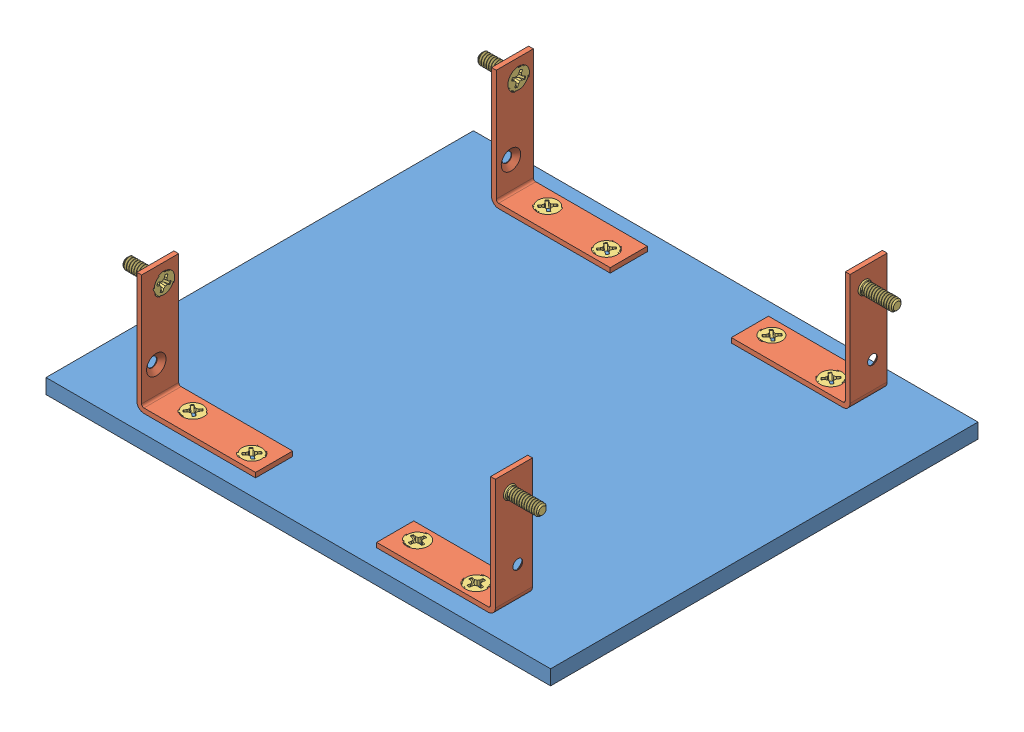
SolidWorks assembly middle shelf, configuration Default. Lengths in mm.
Overall size (215.9 65.04 182.88).
25 component instances, 4 part files, 43 mates.
Components (placement in the parent):
- shelf-1: shelf [Default] at (81.5847 84.2662 165.5831) size (215.9 6.35 182.88)
- 1556A540_BRACKET-1: 1556A540_BRACKET [1556A54] at (4.8767 90.6162 241.4656) x (1 0 0) z (0 1 0) size (50.8 15.88 50.8)
- 1556A540_BRACKET-2: 1556A540_BRACKET [1556A54] at (158.2927 90.6162 241.4656) x (-1 0 0) z (0 1 0) size (50.8 15.88 50.8)
- 1556A540_BRACKET-3: 1556A540_BRACKET [1556A54] at (4.8767 90.6162 89.7006) x (1 0 0) z (0 1 0) size (50.8 15.88 50.8)
- 1556A540_BRACKET-4: 1556A540_BRACKET [1556A54] at (158.2927 90.6162 89.7006) x (-1 0 0) z (0 1 0) size (50.8 15.88 50.8)
- 91771A244_18-8 SS FLAT HEAD PHILLIPS MACHINE SCREW-1: 91771A244_18-8 SS FLAT HEAD PHILLIPS MACHINE SCREW [91771A244] at (19.3547 89.7018 239.8146) x (0.631419 0 -0.775441) z (0 1 0) size (9.19 9.19 16.27)
- 91771A244_18-8 SS FLAT HEAD PHILLIPS MACHINE SCREW-2: 91771A244_18-8 SS FLAT HEAD PHILLIPS MACHINE SCREW [91771A244] at (47.8027 89.7018 243.1166) x (0.630362 0 -0.776302) z (0 1 0) size (9.19 9.19 16.27)
- 91771A244_18-8 SS FLAT HEAD PHILLIPS MACHINE SCREW-3: 91771A244_18-8 SS FLAT HEAD PHILLIPS MACHINE SCREW [91771A244] at (115.3667 89.7018 239.8146) x (0.160382 0 -0.987055) z (0 1 0) size (9.19 9.19 16.27)
- 91771A244_18-8 SS FLAT HEAD PHILLIPS MACHINE SCREW-4: 91771A244_18-8 SS FLAT HEAD PHILLIPS MACHINE SCREW [91771A244] at (143.8147 89.7018 243.1166) x (0.160382 0 -0.987055) z (0 1 0) size (9.19 9.19 16.27)
- 91771A244_18-8 SS FLAT HEAD PHILLIPS MACHINE SCREW-5: 91771A244_18-8 SS FLAT HEAD PHILLIPS MACHINE SCREW [91771A244] at (19.3547 89.7018 88.0496) x (0.631419 0 -0.775441) z (0 1 0) size (9.19 9.19 16.27)
- 91771A244_18-8 SS FLAT HEAD PHILLIPS MACHINE SCREW-6: 91771A244_18-8 SS FLAT HEAD PHILLIPS MACHINE SCREW [91771A244] at (47.8027 89.7018 91.3516) x (0.631419 0 -0.775441) z (0 1 0) size (9.19 9.19 16.27)
- 91771A244_18-8 SS FLAT HEAD PHILLIPS MACHINE SCREW-7: 91771A244_18-8 SS FLAT HEAD PHILLIPS MACHINE SCREW [91771A244] at (115.3667 89.7018 88.0496) x (0.631419 0 -0.775441) z (0 1 0) size (9.19 9.19 16.27)
- 91771A244_18-8 SS FLAT HEAD PHILLIPS MACHINE SCREW-8: 91771A244_18-8 SS FLAT HEAD PHILLIPS MACHINE SCREW [91771A244] at (143.8147 89.7018 91.3516) x (0.631419 0 -0.775441) z (0 1 0) size (9.19 9.19 16.27)
- 91771A244_18-8 SS FLAT HEAD PHILLIPS MACHINE SCREW-9: 91771A244_18-8 SS FLAT HEAD PHILLIPS MACHINE SCREW [91771A244] at (3.9623 133.5422 239.8146) x (0 0.931939 -0.362615) z (1 0 0) size (9.19 9.19 16.27)
- 91771A244_18-8 SS FLAT HEAD PHILLIPS MACHINE SCREW-11: 91771A244_18-8 SS FLAT HEAD PHILLIPS MACHINE SCREW [91771A244] at (3.9623 133.5422 88.0496) x (0 0.931939 -0.362615) z (1 0 0) size (9.19 9.19 16.27)
- 91771A244_18-8 SS FLAT HEAD PHILLIPS MACHINE SCREW-12: 91771A244_18-8 SS FLAT HEAD PHILLIPS MACHINE SCREW [91771A244] at (159.2071 133.5422 91.3516) x (0 -0.881722 -0.471769) z (-1 0 0) size (9.19 9.19 16.27)
- 91771A244_18-8 SS FLAT HEAD PHILLIPS MACHINE SCREW-13: 91771A244_18-8 SS FLAT HEAD PHILLIPS MACHINE SCREW [91771A244] at (159.2071 133.5422 243.1166) x (0 -0.832179 -0.554507) z (-1 0 0) size (9.19 9.19 16.27)
- 90480A011_LOW-STRENGTH STEEL HEX NUT-1: 90480A011_LOW-STRENGTH STEEL HEX NUT [90480A011] at (19.3547 82.6787 239.8146) x (0.837169 0 0.546944) z (-0.546944 0 0.837169) size (9.53 3.99 11)
- 90480A011_LOW-STRENGTH STEEL HEX NUT-2: 90480A011_LOW-STRENGTH STEEL HEX NUT [90480A011] at (47.8027 82.6787 243.1166) x (-0.837169 0 0.546944) z (0.546944 0 0.837169) size (9.53 3.99 11)
- 90480A011_LOW-STRENGTH STEEL HEX NUT-3: 90480A011_LOW-STRENGTH STEEL HEX NUT [90480A011] at (115.3667 82.6787 239.8146) x (-0.837169 0 0.546944) z (0.546944 0 0.837169) size (9.53 3.99 11)
- 90480A011_LOW-STRENGTH STEEL HEX NUT-4: 90480A011_LOW-STRENGTH STEEL HEX NUT [90480A011] at (143.8147 82.6787 243.1166) x (-0.837169 0 0.546944) z (0.546944 0 0.837169) size (9.53 3.99 11)
- 90480A011_LOW-STRENGTH STEEL HEX NUT-5: 90480A011_LOW-STRENGTH STEEL HEX NUT [90480A011] at (19.3547 82.6787 88.0496) x (0.837169 0 0.546944) z (0.546944 0 -0.837169) size (9.53 3.99 11)
- 90480A011_LOW-STRENGTH STEEL HEX NUT-6: 90480A011_LOW-STRENGTH STEEL HEX NUT [90480A011] at (47.8027 82.6787 91.3516) x (-0.401704 0 -0.915769) z (0.915769 0 -0.401704) size (9.53 3.99 11)
- 90480A011_LOW-STRENGTH STEEL HEX NUT-7: 90480A011_LOW-STRENGTH STEEL HEX NUT [90480A011] at (115.3667 82.6787 88.0496) x (0.837169 0 0.546944) z (0.546944 0 -0.837169) size (9.53 3.99 11)
- 90480A011_LOW-STRENGTH STEEL HEX NUT-8: 90480A011_LOW-STRENGTH STEEL HEX NUT [90480A011] at (143.8147 82.6787 91.3516) x (-0.401704 0 -0.915769) z (0.915769 0 -0.401704) size (9.53 3.99 11)
Mates (geometry in assembly coordinates):
- Coincident1: coincident anti-aligned: plane of shelf-1 through (81.5847 90.6162 165.5831) normal (0 1 0); plane of 1556A540_BRACKET-1 through (7.9247 90.6162 233.5281) normal (0 -1 0)
- Distance1: distance = 34.29 mm: line of 1556A540_BRACKET-1 through (7.9247 90.6162 233.5281) axis (0 0 1); line of shelf-1 through (-26.3653 90.6162 74.1431) axis (0 0 1)
- Distance2: distance = 7.62 mm: line of 1556A540_BRACKET-1 through (7.9247 90.6162 249.4031) axis (1 0 0); line of shelf-1 through (-26.3653 90.6162 257.0231) axis (1 0 0)
- Concentric1: concentric aligned: circle of 1556A540_BRACKET-1; circle of 91771A244_18-8 SS FLAT HEAD PHILLIPS MACHINE SCREW-1
- Coincident2: coincident aligned: plane of 1556A540_BRACKET-1 through (7.9247 92.6482 233.5281) normal (0 1 0); plane of 91771A244_18-8 SS FLAT HEAD PHILLIPS MACHINE SCREW-1 through (17.4836 92.6482 238.291) normal (0 1 0)
- Concentric2: concentric aligned: circle of 1556A540_BRACKET-2; circle of 91771A244_18-8 SS FLAT HEAD PHILLIPS MACHINE SCREW-4
- Coincident3: coincident aligned: plane of 1556A540_BRACKET-2 through (155.2447 92.6482 249.4031) normal (0 1 0); plane of 91771A244_18-8 SS FLAT HEAD PHILLIPS MACHINE SCREW-4 through (141.433 92.6482 242.7296) normal (0 1 0)
- Concentric3: concentric aligned: circle of 1556A540_BRACKET-2; circle of 91771A244_18-8 SS FLAT HEAD PHILLIPS MACHINE SCREW-3
- Coincident4: coincident aligned: plane of 1556A540_BRACKET-2 through (155.2447 92.6482 249.4031) normal (0 1 0); plane of 91771A244_18-8 SS FLAT HEAD PHILLIPS MACHINE SCREW-3 through (112.985 92.6482 239.4276) normal (0 1 0)
- Coincident5: coincident aligned: plane of 1556A540_BRACKET-1 through (7.9247 92.6482 233.5281) normal (0 1 0); plane of 91771A244_18-8 SS FLAT HEAD PHILLIPS MACHINE SCREW-2 through (45.9295 92.6482 241.5955) normal (0 1 0)
- Concentric4: concentric aligned: circle of 1556A540_BRACKET-1; circle of 91771A244_18-8 SS FLAT HEAD PHILLIPS MACHINE SCREW-2
- Coincident6: coincident aligned: plane of 1556A540_BRACKET-3 through (7.9247 92.6482 81.7631) normal (0 1 0); plane of 91771A244_18-8 SS FLAT HEAD PHILLIPS MACHINE SCREW-5 through (17.4836 92.6482 86.526) normal (0 1 0)
- Coincident7: coincident aligned: plane of 1556A540_BRACKET-3 through (7.9247 92.6482 81.7631) normal (0 1 0); plane of 91771A244_18-8 SS FLAT HEAD PHILLIPS MACHINE SCREW-6 through (45.9316 92.6482 89.828) normal (0 1 0)
- Concentric5: concentric aligned: cone of 1556A540_BRACKET-3 through (47.8027 90.9006 91.3516) axis (0 -1 0); circle of 91771A244_18-8 SS FLAT HEAD PHILLIPS MACHINE SCREW-6
- Concentric6: concentric aligned: circle of 1556A540_BRACKET-3; circle of 91771A244_18-8 SS FLAT HEAD PHILLIPS MACHINE SCREW-5
- Coincident8: coincident aligned: plane of 1556A540_BRACKET-4 through (155.2447 92.6482 97.6381) normal (0 1 0); plane of 91771A244_18-8 SS FLAT HEAD PHILLIPS MACHINE SCREW-7 through (113.4956 92.6482 86.526) normal (0 1 0)
- Concentric7: concentric aligned: circle of 1556A540_BRACKET-4; circle of 91771A244_18-8 SS FLAT HEAD PHILLIPS MACHINE SCREW-7
- Coincident9: coincident aligned: plane of 1556A540_BRACKET-4 through (155.2447 92.6482 97.6381) normal (0 1 0); plane of 91771A244_18-8 SS FLAT HEAD PHILLIPS MACHINE SCREW-8 through (141.9436 92.6482 89.828) normal (0 1 0)
- Concentric8: concentric aligned: circle of 1556A540_BRACKET-4; circle of 91771A244_18-8 SS FLAT HEAD PHILLIPS MACHINE SCREW-8
- Coincident12: coincident aligned: plane of 1556A540_BRACKET-1 through (6.9087 141.4162 233.5281) normal (1 0 0); plane of 91771A244_18-8 SS FLAT HEAD PHILLIPS MACHINE SCREW-9 through (6.9087 134.4172 242.0634) normal (1 0 0)
- Concentric9: concentric aligned: circle of 1556A540_BRACKET-1; circle of 91771A244_18-8 SS FLAT HEAD PHILLIPS MACHINE SCREW-9
- Coincident13: coincident aligned: plane of 1556A540_BRACKET-3 through (6.9087 141.4162 81.7631) normal (1 0 0); plane of 91771A244_18-8 SS FLAT HEAD PHILLIPS MACHINE SCREW-11 through (6.9087 134.4172 90.2984) normal (1 0 0)
- Concentric10: concentric aligned: circle of 1556A540_BRACKET-3; circle of 91771A244_18-8 SS FLAT HEAD PHILLIPS MACHINE SCREW-11
- Coincident14: coincident aligned: plane of 1556A540_BRACKET-4 through (156.2607 141.4162 97.6381) normal (-1 0 0); plane of 91771A244_18-8 SS FLAT HEAD PHILLIPS MACHINE SCREW-12 through (156.2607 132.4039 93.4792) normal (-1 0 0)
- Concentric11: concentric aligned: circle of 1556A540_BRACKET-4; circle of 91771A244_18-8 SS FLAT HEAD PHILLIPS MACHINE SCREW-12
- Concentric12: concentric aligned: circle of 1556A540_BRACKET-2; circle of 91771A244_18-8 SS FLAT HEAD PHILLIPS MACHINE SCREW-13
- Coincident15: coincident aligned: plane of 1556A540_BRACKET-2 through (156.2607 141.4162 249.4031) normal (-1 0 0); plane of 91771A244_18-8 SS FLAT HEAD PHILLIPS MACHINE SCREW-13 through (156.2607 132.2042 245.1246) normal (-1 0 0)
- Coincident17: coincident anti-aligned: plane of shelf-1 through (81.5847 84.2662 165.5831) normal (0 -1 0); plane of 90480A011_LOW-STRENGTH STEEL HEX NUT-1 through (16.8716 84.2662 234.9079) normal (0 1 0)
- Concentric13: concentric anti-aligned: circle of 91771A244_18-8 SS FLAT HEAD PHILLIPS MACHINE SCREW-1; circle of 90480A011_LOW-STRENGTH STEEL HEX NUT-1
- Concentric14: concentric aligned: circle of 91771A244_18-8 SS FLAT HEAD PHILLIPS MACHINE SCREW-2; circle of 90480A011_LOW-STRENGTH STEEL HEX NUT-2
- Coincident18: coincident anti-aligned: plane of shelf-1 through (81.5847 84.2662 165.5831) normal (0 -1 0); plane of 90480A011_LOW-STRENGTH STEEL HEX NUT-2 through (50.2859 84.2662 238.2099) normal (0 1 0)
- Concentric15: concentric aligned: circle of 91771A244_18-8 SS FLAT HEAD PHILLIPS MACHINE SCREW-3; circle of 90480A011_LOW-STRENGTH STEEL HEX NUT-3
- Concentric16: concentric aligned: circle of 91771A244_18-8 SS FLAT HEAD PHILLIPS MACHINE SCREW-4; circle of 90480A011_LOW-STRENGTH STEEL HEX NUT-4
- Coincident19: coincident anti-aligned: plane of shelf-1 through (81.5847 84.2662 165.5831) normal (0 -1 0); plane of 90480A011_LOW-STRENGTH STEEL HEX NUT-3 through (117.8499 84.2662 234.9079) normal (0 1 0)
- Coincident20: coincident anti-aligned: plane of shelf-1 through (81.5847 84.2662 165.5831) normal (0 -1 0); plane of 90480A011_LOW-STRENGTH STEEL HEX NUT-4 through (146.2979 84.2662 238.2099) normal (0 1 0)
- Coincident211: coincident anti-aligned: plane of shelf-1 through (81.5847 84.2662 165.5831) normal (0 -1 0); plane of 90480A011_LOW-STRENGTH STEEL HEX NUT-5 through (13.8638 84.2662 87.7467) normal (0 1 0)
- Coincident221: coincident anti-aligned: plane of shelf-1 through (81.5847 84.2662 165.5831) normal (0 -1 0); plane of 90480A011_LOW-STRENGTH STEEL HEX NUT-6 through (47.1978 84.2662 96.8175) normal (0 1 0)
- Coincident231: coincident anti-aligned: plane of shelf-1 through (81.5847 84.2662 165.5831) normal (0 -1 0); plane of 90480A011_LOW-STRENGTH STEEL HEX NUT-7 through (109.8758 84.2662 87.7467) normal (0 1 0)
- Coincident241: coincident anti-aligned: plane of shelf-1 through (81.5847 84.2662 165.5831) normal (0 -1 0); plane of 90480A011_LOW-STRENGTH STEEL HEX NUT-8 through (143.2098 84.2662 96.8175) normal (0 1 0)
- Concentric17: concentric anti-aligned: circle of 91771A244_18-8 SS FLAT HEAD PHILLIPS MACHINE SCREW-6; circle of 90480A011_LOW-STRENGTH STEEL HEX NUT-6
- Concentric18: concentric aligned: circle of 91771A244_18-8 SS FLAT HEAD PHILLIPS MACHINE SCREW-5; circle of 90480A011_LOW-STRENGTH STEEL HEX NUT-5
- Concentric19: concentric aligned: circle of 91771A244_18-8 SS FLAT HEAD PHILLIPS MACHINE SCREW-7; circle of 90480A011_LOW-STRENGTH STEEL HEX NUT-7
- Concentric20: concentric anti-aligned: circle of 91771A244_18-8 SS FLAT HEAD PHILLIPS MACHINE SCREW-8; circle of 90480A011_LOW-STRENGTH STEEL HEX NUT-8
